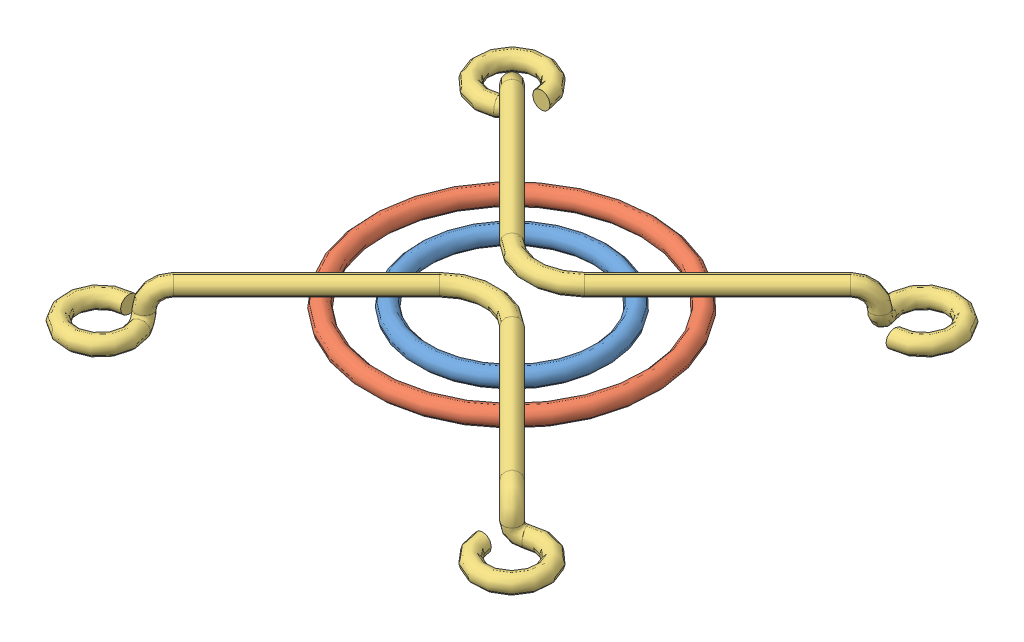
SolidWorks assembly LZ29-1_ebm-papst, configuration LZ29-1_ebm-papst. Lengths in mm.
Overall size (47.4 4.75 47.4).
4 component instances, 3 part files, 8 mates.
Components (placement in the parent):
- Ring2_LZ29-1_ebm-papst-1: Ring2_LZ29-1_ebm-papst [LZ29-1_ebm-papst] at origin size (18.78 1.7 18.78)
- Ring1_LZ29-1_ebm-papst-1: Ring1_LZ29-1_ebm-papst [LZ29-1_ebm-papst] at origin size (28.06 1.7 28.06)
- Fix_LZ29-1_ebm-papst-1: Fix_LZ29-1_ebm-papst [LZ29-1_ebm-papst] at (0 -1.3507 0) size (47.4 4.75 22.49)
- Fix_LZ29-1_ebm-papst-2: Fix_LZ29-1_ebm-papst [LZ29-1_ebm-papst] at (0 -1.3507 0) x (-1 0 0) z (0 0 -1) size (47.4 4.75 22.49)
Mates (geometry in assembly coordinates):
- Coincident1: coincident anti-aligned: plane of Fix_LZ29-1_ebm-papst-2 through (0 -1.3507 0) normal (0 0 -1); plane of assembly through (0 0 0) normal (0 0 1)
- Coincident3: coincident anti-aligned: plane of Fix_LZ29-1_ebm-papst-2 through (0 -1.3507 0) normal (-1 0 0); plane of assembly through (0 0 0) normal (1 0 0)
- Coincident4: coincident aligned: plane of Fix_LZ29-1_ebm-papst-1 through (0 -1.3507 0) normal (0 0 1); plane of assembly through (0 0 0) normal (0 0 1)
- Coincident5: coincident aligned: plane of Fix_LZ29-1_ebm-papst-1 through (0 -1.3507 0) normal (1 0 0); plane of assembly through (0 0 0) normal (1 0 0)
- Coincident6: coincident aligned: plane of Ring2_LZ29-1_ebm-papst-1 through (0 0.85 0) normal (0 1 0); plane of Fix_LZ29-1_ebm-papst-1 through (0 0.85 0) normal (0 1 0)
- Coincident7: coincident aligned: plane of Ring1_LZ29-1_ebm-papst-1 through (0 0.85 0) normal (0 1 0); plane of Fix_LZ29-1_ebm-papst-1 through (0 0.85 0) normal (0 1 0)
- Coincident8: coincident aligned: plane of Ring2_LZ29-1_ebm-papst-1 through (0 0.85 0) normal (0 1 0); plane of Fix_LZ29-1_ebm-papst-2
- Coincident9: coincident aligned: plane of Ring1_LZ29-1_ebm-papst-1 through (0 0.85 0) normal (0 1 0); plane of Fix_LZ29-1_ebm-papst-2
